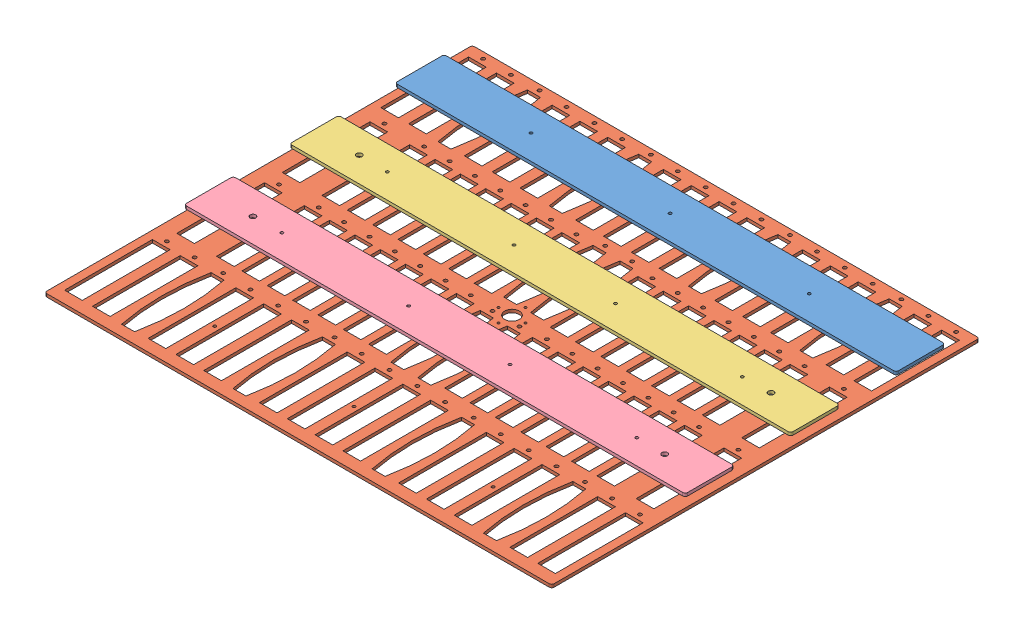
SolidWorks assembly pfc_panel_assembly, configuration Default. Lengths in mm.
Overall size (525.46 12.7 443.28).
4 component instances, 4 part files, 9 mates.
Components (placement in the parent):
- backstrap01-1: backstrap01 [Default] at (19.3148 0.4483 -11.5752) size (519.11 3.17 50.8)
- pfc_panel-1: pfc_panel [Default] at (19.3148 -9.0767 152.2522) size (525.46 3.17 443.28)
- backstrap02-1: backstrap02 [Default] at (19.3148 0.4483 97.6956) size (519.11 3.17 50.8)
- backstrap03-1: backstrap03 [Default] at (19.3148 0.4483 206.9664) size (519.11 3.17 50.8)
Mates (geometry in assembly coordinates):
- Distance1: distance = 6.35 mm anti-aligned: plane of backstrap01-1 through (19.3148 0.4483 -11.5752) normal (0 -1 0); plane of pfc_panel-1 through (19.3148 -5.9017 152.2522) normal (0 1 0)
- Distance2: distance = 3.175 mm aligned: plane of backstrap01-1 through (278.871 3.6233 13.8248) normal (1 0 0); plane of pfc_panel-1 through (282.046 -5.9017 373.8901) normal (1 0 0)
- Distance3: distance = 32.4104 mm aligned: plane of backstrap01-1 through (-240.2415 3.6233 -36.9752) normal (0 0 -1); plane of pfc_panel-1 through (-243.4165 -5.9017 -69.3856) normal (0 0 -1)
- Distance4: distance = 6.35 mm anti-aligned: plane of backstrap02-1 through (19.3148 0.4483 97.6956) normal (0 -1 0); plane of pfc_panel-1 through (19.3148 -5.9017 152.2522) normal (0 1 0)
- Distance5: distance = 3.175 mm aligned: plane of pfc_panel-1 through (282.046 -5.9017 373.8901) normal (1 0 0); plane of backstrap02-1 through (278.871 3.6233 123.0956) normal (1 0 0)
- Distance6: distance = 20.066 mm anti-aligned: plane of backstrap02-1 through (-240.2415 3.6233 72.2956) normal (0 0 -1); plane of pfc_panel-1 through (49.7789 -9.0767 52.2296) normal (0 0 1)
- Concentric1: concentric: circle of pfc_panel-1; circle of backstrap03-1
- Concentric2: concentric: circle of pfc_panel-1; circle of backstrap03-1
- Distance8: distance = 6.35 mm anti-aligned: plane of pfc_panel-1 through (19.3148 -5.9017 152.2522) normal (0 1 0); plane of backstrap03-1 through (19.3148 0.4483 206.9664) normal (0 -1 0)
